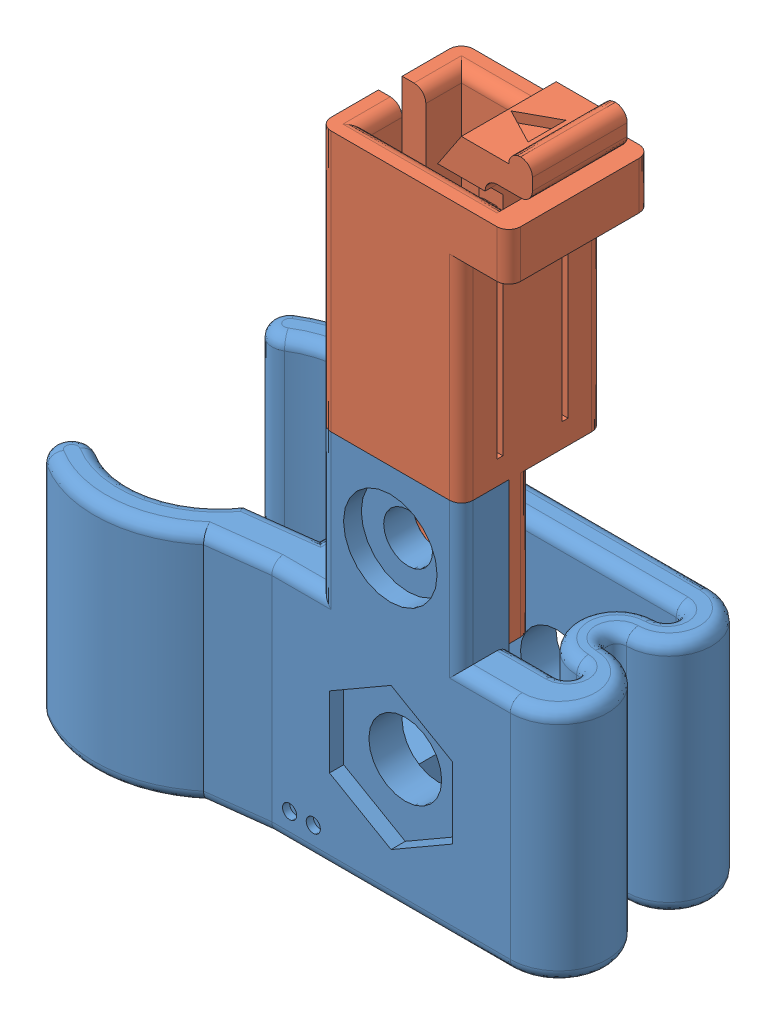
SolidWorks assembly CauteryTracking-Concept, configuration Default. Lengths in mm.
Overall size (42.4 58.16 24.2).
2 component instances, 2 part files, 3 mates.
Components (placement in the parent):
- CauteryGrabber-1: CauteryGrabber [Default] at (2.0061 10.1548 40.0575) size (42.4 32.06 24.2)
- SensorHolder-OneHole-1: SensorHolder-OneHole [Default] at (26.8901 49.7265 50.6141) x (-1 0 0) z (0 0 -1) size (16 38.1 12)
Mates (geometry in assembly coordinates):
- Coincident1: coincident anti-aligned: plane of CauteryGrabber-1 through (13.88 30.1548 45.0575) normal (0 0 -1); plane of SensorHolder-OneHole-1 through (17.88 30.1548 45.0575) normal (0 0 1)
- Coincident2: coincident anti-aligned: plane of CauteryGrabber-1 through (2.0061 42.1548 40.0575) normal (0 1 0); plane of SensorHolder-OneHole-1 through (27.6122 42.1548 45.089) normal (0 -1 0)
- Concentric1: concentric anti-aligned: circle of CauteryGrabber-1; circle of SensorHolder-OneHole-1
